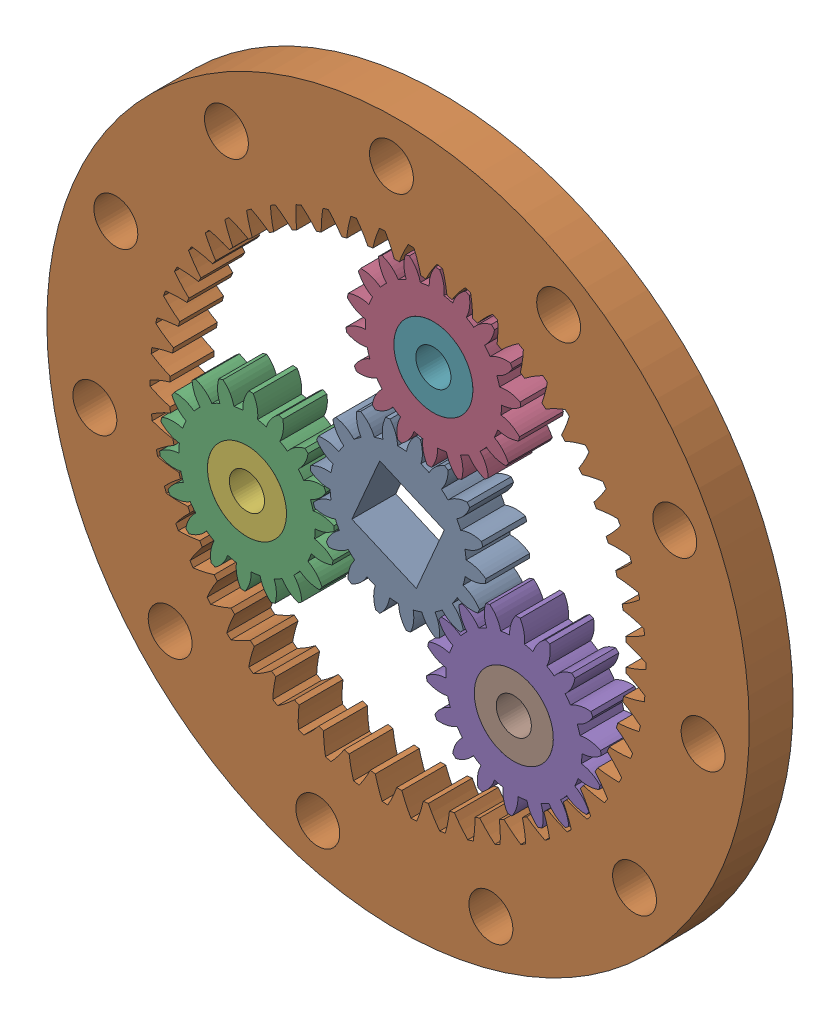
SolidWorks assembly RR_20238_50New Gear Assembly_V2_27_29_10 pm_31_12pm_9pm, configuration Default. Lengths in mm.
Overall size (112.65 112.65 5).
8 component instances, 4 part files, 10 mates.
Components (placement in the parent):
- RR_20238_50New Sun gear_V2_27_29_10 pm_31_12pm_9pm-1: RR_20238_50New Sun gear_V2_27_29_10 pm_31_12pm_9pm [Metric - Spur gear 1M 18T 20PA 5FW ---S18N75H50L5N] at (0 0 5) x (0 0 -1) z (-0.918048 0.396468 0) size (5 19.78 20)
- RR_20238_50New Ring Gear_V2_27_29_10 pm_31_12pm_9pm-1: RR_20238_50New Ring Gear_V2_27_29_10 pm_31_12pm_9pm [Metric - Internal spur gear 1M 54T 20PA 5FW ---S54S80OD 1AF] x (0 0 1) z (0.638551 0.76958 0) size (5 80 80)
- RR_20238_50New Planet gear_V2_27_29_10 pm_31_12pm_9pm-1: RR_20238_50New Planet gear_V2_27_29_10 pm_31_12pm_9pm [Metric - Spur gear 1M 18T 20PA 5FW ---S18N75H50L5N] at (-17.2058 -5.2877 0) x (0 0 1) z (0.975503 -0.219985 0) size (5 19.78 20)
- RR_20238_50New Planet gear_V2_27_29_10 pm_31_12pm_9pm-2: RR_20238_50New Planet gear_V2_27_29_10 pm_31_12pm_9pm [Metric - Spur gear 1M 18T 20PA 5FW ---S18N75H50L5N] at (4.0237 17.5445 0) x (0 0 1) z (-0.678264 -0.734818 0) size (5 19.78 20)
- RR_20238_50New Planet gear_V2_27_29_10 pm_31_12pm_9pm-3: RR_20238_50New Planet gear_V2_27_29_10 pm_31_12pm_9pm [Metric - Spur gear 1M 18T 20PA 5FW ---S18N75H50L5N] at (13.1822 -12.2569 0) x (0 0 1) z (-0.297239 0.954803 0) size (5 19.78 20)
- RR_20238_504_9_4 Ball bearing_V2_27_29_10 pm_31_12pm_9pm-1: RR_20238_504_9_4 Ball bearing_V2_27_29_10 pm_31_12pm_9pm [Default] at (-17.2058 -5.2877 1) x (0.877867 -0.478905 0) z (0 0 1) size (9 9 4)
- RR_20238_504_9_4 Ball bearing_V2_27_29_10 pm_31_12pm_9pm-2: RR_20238_504_9_4 Ball bearing_V2_27_29_10 pm_31_12pm_9pm [Default] at (4.0237 17.5445 1) x (-0.853677 -0.520803 0) z (0 0 1) size (9 9 4)
- RR_20238_504_9_4 Ball bearing_V2_27_29_10 pm_31_12pm_9pm-3: RR_20238_504_9_4 Ball bearing_V2_27_29_10 pm_31_12pm_9pm [Default] at (13.1822 -12.2569 1) x (-0.02419 0.999707 0) z (0 0 1) size (9 9 4)
Mates (geometry in assembly coordinates):
- Concentric1: concentric anti-aligned: cylinder of RR_20238_50New Ring Gear_V2_27_29_10 pm_31_12pm_9pm-1 through (0 0 -10) axis (0 0 -1) radius 40
- Coincident3: coincident aligned: plane of RR_20238_50New Sun gear_V2_27_29_10 pm_31_12pm_9pm-1 through (0 0 5) normal (0 0 1); plane of RR_20238_50New Ring Gear_V2_27_29_10 pm_31_12pm_9pm-1 through (-16.6023 -20.0091 5) normal (0 0 1)
- Coincident4: coincident anti-aligned: plane of RR_20238_50New Ring Gear_V2_27_29_10 pm_31_12pm_9pm-1 through (-16.6023 -20.0091 0) normal (0 0 -1)
- Concentric4: concentric aligned: cylinder of RR_20238_50New Sun gear_V2_27_29_10 pm_31_12pm_9pm-1 through (0 0 0) axis (0 0 1) radius 7.749
- Coincident7: coincident: point of RR_20238_50New Planet gear_V2_27_29_10 pm_31_12pm_9pm-1; circle of assembly
- Coincident8: coincident aligned: plane of RR_20238_50New Ring Gear_V2_27_29_10 pm_31_12pm_9pm-1 through (-16.6023 -20.0091 0) normal (0 0 -1); plane of RR_20238_50New Planet gear_V2_27_29_10 pm_31_12pm_9pm-1 through (-17.2058 -5.2877 0) normal (0 0 -1)
- GearMate1: gear = 1 : 1 mm: cylinder of RR_20238_50New Sun gear_V2_27_29_10 pm_31_12pm_9pm-1 through (0 0 0) axis (0 0 1) radius 7.749; cylinder of RR_20238_50New Planet gear_V2_27_29_10 pm_31_12pm_9pm-1 through (-17.2058 -5.2877 5) axis (0 0 -1) radius 7.749
- GearMate2: gear = 3 : 1 mm: cylinder of RR_20238_50New Planet gear_V2_27_29_10 pm_31_12pm_9pm-1 through (-17.2058 -5.2877 1) axis (0 0 1) radius 4.5; cylinder of RR_20238_50New Ring Gear_V2_27_29_10 pm_31_12pm_9pm-1 through (0 0 -10) axis (0 0 -1) radius 40
- Concentric6: concentric anti-aligned: cylinder of RR_20238_50New Planet gear_V2_27_29_10 pm_31_12pm_9pm-1 through (-17.2058 -5.2877 1) axis (0 0 1) radius 4.5; cylinder of 4_9_4 Ball bearing-1 through (-17.2058 -5.2877 5) axis (0 0 -1) radius 2
- Coincident9: coincident anti-aligned: plane of RR_20238_50New Planet gear_V2_27_29_10 pm_31_12pm_9pm-1 through (-17.2058 -5.2877 1) normal (0 0 1); plane of 4_9_4 Ball bearing-1 through (-17.2058 -5.2877 1) normal (0 0 -1)
